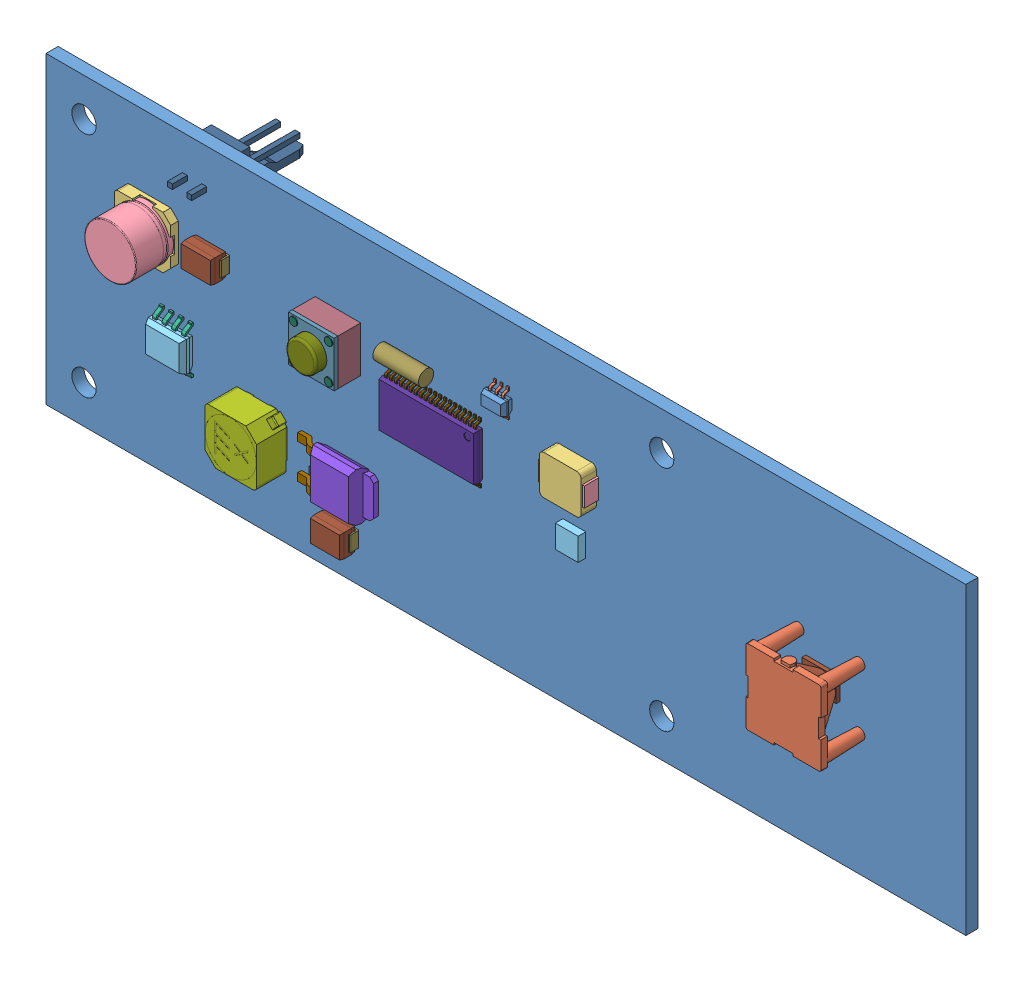
SolidWorks assembly CarteECLAI-YC, configuration Défaut. Lengths in mm.
Overall size (121 40 19.3).
110 component instances, 34 part files, 55 mates.
Components (placement in the parent):
- PCB-1: PCB [Défaut] at (-79.5148 -10.7674 -0.8) size (121 40 1.6)
- Lentille-1: Lentille [Défaut] at (23.4852 9.2326 6.65) x (-1 0 0) z (0 0 -1) size (9.9 9.95 6.4)
- C1-1: C1 [Défaut] at (-27.7034 54.9496 1.55) x (0 1 0) z (0 0 1) size (6.9 6.9 5.5)
  - C1_embase-1: C1_embase [Défaut] at (-42.0171 34.4114 -0.75) size (6.9 6.9 1.5)
  - C1_boitier-1: C1_boitier [Défaut] at (-38.5671 37.8614 -0.25) size (6.8 6.8 5)
- U1-1: U1 [Défaut] at (-30.9157 -18.9411 1.8647) size (5 6.2 1.94)
  - U1_boitier-1: U1_boitier [Défaut] at (-33.8554 22.1141 -0.875) size (5 4 1.75)
  - U1_pin-1: U1_pin [Défaut] at (-32.2404 26.1141 -0.875) x (-1 0 0) z (0 0 1) size (0.5 1.1 1.09)
  - U1_pin-2: U1_pin [Défaut] at (-33.5104 26.1141 -0.875) x (-1 0 0) z (0 0 1) size (0.5 1.1 1.09)
  - U1_pin-3: U1_pin [Défaut] at (-30.9704 26.1141 -0.875) x (-1 0 0) z (0 0 1) size (0.5 1.1 1.09)
  - U1_pin-4: U1_pin [Défaut] at (-29.7004 26.1141 -0.875) x (-1 0 0) z (0 0 1) size (0.5 1.1 1.09)
  - U1_pin-5: U1_pin [Défaut] at (-31.7404 22.1141 -0.875) size (0.5 1.1 1.09)
  - U1_pin-6: U1_pin [Défaut] at (-33.0104 22.1141 -0.875) size (0.5 1.1 1.09)
  - U1_pin-7: U1_pin [Défaut] at (-30.4704 22.1141 -0.875) size (0.5 1.1 1.09)
  - U1_pin-8: U1_pin [Défaut] at (-29.2004 22.1141 -0.875) size (0.5 1.1 1.09)
- L1-1: L1 [Default] at (-51.1156 0.6301 1) x (0 1 0) z (1 0 0) size (7.56 4.1 7.56)
- Q1-1: Q1 [Défaut] at (-47.9587 -45.8219 1.895) x (0 -1 0) z (0 0 1) size (6.35 10.04 2.19)
  - Q1_boitier-1: Q1_boitier [Défaut] at (-49.4045 4.9439 -1.095) size (6.35 7.24 2.19)
  - Q1_Pin-1: Q1_Pin [Défaut] at (-49.0095 2.1439 -0.505) x (0 0 -1) z (1 0 0) size (1.3 2.8 1)
  - Q1_Pin2-1: Q1_Pin2 [Défaut] at (-45.7295 5.2439 2.6813) x (0 1 0) z (-1 0 0) size (0.5 0.41 1)
  - Q1_Pin-2: Q1_Pin [Défaut] at (-44.4495 2.1439 -0.505) x (0 0 -1) z (1 0 0) size (1.3 2.8 1)
- D3-1: D3 [Défaut] at (-11.1435 -5.4674 2.6964) x (1 0 0) z (0 -1 0) size (4.4 2.3 3)
  - D3_boitier-1: D3_boitier [Défaut] at (-31.3713 -1.5964 1.5) size (4 2 3)
  - D3_pin-1: D3_pin [Défaut] at (-31.5713 -1.8964 -0.98) size (0.5 1.2 2)
  - D3_pin-2: D3_pin [Défaut] at (-27.1713 -1.8964 1.02) x (-1 0 0) z (0 0 -1) size (0.5 1.2 2)
- D3-2: D3 [Défaut] at (-28.1435 17.3326 2.6964) x (1 0 0) z (0 -1 0) size (4.4 2.3 3)
  - D3_boitier-1: D3_boitier [Défaut] at (-31.3713 -1.5964 1.5) size (4 2 3)
  - D3_pin-1: D3_pin [Défaut] at (-31.5713 -1.8964 -0.98) size (0.5 1.2 2)
  - D3_pin-2: D3_pin [Défaut] at (-27.1713 -1.8964 1.02) x (-1 0 0) z (0 0 -1) size (0.5 1.2 2)
- Switch-1: Switch [Défaut] at (-30.8503 16.2326 10.8345) x (1 0 0) z (0 -1 0) size (6 4.89 6)
  - Switch_Corps-1: Switch_Corps [Défaut] at (-13.2645 -10.0345 3) size (6 3 6)
  - Switch_Couvercle-1: Switch_Couvercle [Défaut] at (-13.2645 -7.0345 3) size (6 0.5 6)
  - Switch_Seri-1: Switch_Seri [Défaut] at (-12.5686 -6.4345 2.3041) x (-0.837169 0 -0.546944) z (-0.546944 0 0.837169) size (1 0.6 1)
  - Switch_Seri-2: Switch_Seri [Défaut] at (-7.9603 -6.4345 -2.3041) x (-0.837169 0 -0.546944) z (-0.546944 0 0.837169) size (1 0.6 1)
  - Switch_Seri-3: Switch_Seri [Défaut] at (-7.9603 -6.4345 2.3041) x (-0.837169 0 -0.546944) z (-0.546944 0 0.837169) size (1 0.6 1)
  - Switch_Seri-4: Switch_Seri [Défaut] at (-12.5686 -6.4345 -2.3041) x (-0.837169 0 -0.546944) z (-0.546944 0 0.837169) size (1 0.6 1)
  - Switch_Bp-1: Switch_Bp [Défaut] at (-10.2645 -8.1417 0) x (0.988647 0 0.150258) z (-0.150258 0 0.988647) size (4 3 4)
- U2-1: U2 [Défaut] at (-16.9345 12.3907 -2.7862) x (-1 0 0) z (0 1 0) size (12.6 1.27 7.96)
  - U2_Boitier-1: U2_Boitier [Défaut] at (4.9869 3.6612 3) size (12.6 1.2 6)
  - U2_Pin-1: U2_Pin [Défaut] at (11.1369 3.5862 3.9812) x (0 0 -1) z (1 0 0) size (0.98 0.78 0.3)
  - U2_Pin-2: U2_Pin [Défaut] at (10.4869 3.5862 3.9812) x (0 0 -1) z (1 0 0) size (0.98 0.78 0.3)
  - U2_Pin-3: U2_Pin [Défaut] at (9.8369 3.5862 3.9812) x (0 0 -1) z (1 0 0) size (0.98 0.78 0.3)
  - U2_Pin-4: U2_Pin [Défaut] at (9.1869 3.5862 3.9812) x (0 0 -1) z (1 0 0) size (0.98 0.78 0.3)
  - U2_Pin-5: U2_Pin [Défaut] at (8.5369 3.5862 3.9812) x (0 0 -1) z (1 0 0) size (0.98 0.78 0.3)
  - U2_Pin-6: U2_Pin [Défaut] at (7.8869 3.5862 3.9812) x (0 0 -1) z (1 0 0) size (0.98 0.78 0.3)
  - U2_Pin-7: U2_Pin [Défaut] at (7.2369 3.5862 3.9812) x (0 0 -1) z (1 0 0) size (0.98 0.78 0.3)
  - U2_Pin-8: U2_Pin [Défaut] at (6.5869 3.5862 3.9812) x (0 0 -1) z (1 0 0) size (0.98 0.78 0.3)
  - U2_Pin-9: U2_Pin [Défaut] at (5.9369 3.5862 3.9812) x (0 0 -1) z (1 0 0) size (0.98 0.78 0.3)
  - U2_Pin-12: U2_Pin [Défaut] at (11.7869 3.5862 3.9812) x (0 0 -1) z (1 0 0) size (0.98 0.78 0.3)
  - U2_Pin-13: U2_Pin [Défaut] at (12.4369 3.5862 3.9812) x (0 0 -1) z (1 0 0) size (0.98 0.78 0.3)
  - U2_Pin-14: U2_Pin [Défaut] at (13.0869 3.5862 3.9812) x (0 0 -1) z (1 0 0) size (0.98 0.78 0.3)
  - U2_Pin-15: U2_Pin [Défaut] at (13.7369 3.5862 3.9812) x (0 0 -1) z (1 0 0) size (0.98 0.78 0.3)
  - U2_Pin-16: U2_Pin [Défaut] at (14.3869 3.5862 3.9812) x (0 0 -1) z (1 0 0) size (0.98 0.78 0.3)
  - U2_Pin-17: U2_Pin [Défaut] at (15.0369 3.5862 3.9812) x (0 0 -1) z (1 0 0) size (0.98 0.78 0.3)
  - U2_Pin-18: U2_Pin [Défaut] at (15.6869 3.5862 3.9812) x (0 0 -1) z (1 0 0) size (0.98 0.78 0.3)
  - U2_Pin-19: U2_Pin [Défaut] at (16.3369 3.5862 3.9812) x (0 0 -1) z (1 0 0) size (0.98 0.78 0.3)
  - U2_Pin-21: U2_Pin [Défaut] at (5.2869 3.5862 3.9812) x (0 0 -1) z (1 0 0) size (0.98 0.78 0.3)
  - U2_Pin-22: U2_Pin [Défaut] at (16.9869 3.5862 3.9812) x (0 0 -1) z (1 0 0) size (0.98 0.78 0.3)
  - U2_Pin-23: U2_Pin [Défaut] at (11.4369 3.5862 -3.9812) x (0 0 1) z (-1 0 0) size (0.98 0.78 0.3)
  - U2_Pin-24: U2_Pin [Défaut] at (12.0869 3.5862 -3.9812) x (0 0 1) z (-1 0 0) size (0.98 0.78 0.3)
  - U2_Pin-26: U2_Pin [Défaut] at (12.7369 3.5862 -3.9812) x (0 0 1) z (-1 0 0) size (0.98 0.78 0.3)
  - U2_Pin-27: U2_Pin [Défaut] at (13.3869 3.5862 -3.9812) x (0 0 1) z (-1 0 0) size (0.98 0.78 0.3)
  - U2_Pin-28: U2_Pin [Défaut] at (14.0369 3.5862 -3.9812) x (0 0 1) z (-1 0 0) size (0.98 0.78 0.3)
  - U2_Pin-29: U2_Pin [Défaut] at (14.6869 3.5862 -3.9812) x (0 0 1) z (-1 0 0) size (0.98 0.78 0.3)
  - U2_Pin-30: U2_Pin [Défaut] at (15.3369 3.5862 -3.9812) x (0 0 1) z (-1 0 0) size (0.98 0.78 0.3)
  - U2_Pin-31: U2_Pin [Défaut] at (15.9869 3.5862 -3.9812) x (0 0 1) z (-1 0 0) size (0.98 0.78 0.3)
  - U2_Pin-32: U2_Pin [Défaut] at (16.6369 3.5862 -3.9812) x (0 0 1) z (-1 0 0) size (0.98 0.78 0.3)
  - U2_Pin-33: U2_Pin [Défaut] at (17.2869 3.5862 -3.9812) x (0 0 1) z (-1 0 0) size (0.98 0.78 0.3)
  - U2_Pin-34: U2_Pin [Défaut] at (10.7869 3.5862 -3.9812) x (0 0 1) z (-1 0 0) size (0.98 0.78 0.3)
  - U2_Pin-35: U2_Pin [Défaut] at (10.1369 3.5862 -3.9812) x (0 0 1) z (-1 0 0) size (0.98 0.78 0.3)
  - U2_Pin-36: U2_Pin [Défaut] at (9.4869 3.5862 -3.9812) x (0 0 1) z (-1 0 0) size (0.98 0.78 0.3)
  - U2_Pin-37: U2_Pin [Défaut] at (8.8369 3.5862 -3.9812) x (0 0 1) z (-1 0 0) size (0.98 0.78 0.3)
  - U2_Pin-38: U2_Pin [Défaut] at (8.1869 3.5862 -3.9812) x (0 0 1) z (-1 0 0) size (0.98 0.78 0.3)
  - U2_Pin-39: U2_Pin [Défaut] at (7.5369 3.5862 -3.9812) x (0 0 1) z (-1 0 0) size (0.98 0.78 0.3)
  - U2_Pin-40: U2_Pin [Défaut] at (6.8869 3.5862 -3.9812) x (0 0 1) z (-1 0 0) size (0.98 0.78 0.3)
  - U2_Pin-41: U2_Pin [Défaut] at (6.2369 3.5862 -3.9812) x (0 0 1) z (-1 0 0) size (0.98 0.78 0.3)
  - U2_Pin-42: U2_Pin [Défaut] at (5.5869 3.5862 -3.9812) x (0 0 1) z (-1 0 0) size (0.98 0.78 0.3)
- U3-1: U3 [Défaut] at (-9.125 -11.1977 1.55) size (3 3.71 1.47)
  - U3_boitier-1: U3_boitier [Défaut] at (-11.8964 30.2254 -0.725) size (3 1.75 1.45)
  - U3_Pin-1: U3_Pin [Défaut] at (-10.5464 30.2254 0.025) x (0 -1 0) z (1 0 0) size (0.98 0.78 0.3)
  - U3_Pin-2: U3_Pin [Défaut] at (-11.3964 30.2254 0.025) x (0 -1 0) z (1 0 0) size (0.98 0.78 0.3)
  - U3_Pin-5: U3_Pin [Défaut] at (-9.6964 30.2254 0.025) x (0 -1 0) z (1 0 0) size (0.98 0.78 0.3)
  - U3_Pin-6: U3_Pin [Défaut] at (-10.2464 32.9566 -0.75) x (0 -1 0) z (-1 0 0) size (0.98 0.78 0.3)
  - U3_Pin-7: U3_Pin [Défaut] at (-11.0964 32.9566 -0.75) x (0 -1 0) z (-1 0 0) size (0.98 0.78 0.3)
  - U3_Pin-8: U3_Pin [Défaut] at (-9.3964 32.9566 -0.75) x (0 -1 0) z (-1 0 0) size (0.98 0.78 0.3)
- L2-1: L2 [Défaut] at (28.7972 -10.0998 1.9) size (6.05 5.18 2.1)
  - L2_boitier-1: L2_boitier [Défaut] at (-41.3121 23.5524 -1) size (5.49 5.18 2)
  - L2_pin-1: L2_pin [Défaut] at (-35.8421 24.8724 -0.8) x (-1 0 0) z (0 0 -1) size (1.3 2.54 1.95)
  - L2_pin-2: L2_pin [Défaut] at (-41.2921 27.4124 -0.8) x (1 0 0) z (0 0 -1) size (1.3 2.54 1.95)
- U4-1: U4 [Défaut] at (-11.5148 7.2326 0.8) size (3 3 1)
- R_J6-1: R_J6 [Défaut] at (-48.0148 -7.2951 -15.102) x (0 -0.870538 0.492102) z (-1 0 0) size (4.71 4.44 24.2)
  - R_corps-1: R_corps [Défaut] at (-14.9486 23.7304 -11.5) size (2 2 23)
  - R_fil-1: R_fil [Défaut] at (-14.9486 23.7304 -11.5) x (0.735085 -0.677975 0) z (0.677975 0.735085 0) size (5.06 11.19 0.2)
  - R_fil-2: R_fil [Défaut] at (-14.9486 23.7304 11.5) x (0.735085 -0.677975 0) z (-0.677975 -0.735085 0) size (5.06 11.19 0.2)
- R_J5_J17-1: R_J5_J17 [Défaut] at (-1.4671 6.7792 26.1941) x (-0.812051 0 0.583586) z (0 -1 0) size (4.54 4.6 24.2)
  - R_corps-1: R_corps [Défaut] at (-14.9486 23.7304 -11.5) size (2 2 23)
  - R_fil_court-2: R_fil_court [Défaut] at (-14.9486 23.7304 11.5) x (0.700956 0.713204 0) z (0.713204 -0.700956 0) size (4.95 5.14 0.2)
  - R_fil_long-4: R_fil_long [Défaut] at (-14.9486 23.7304 -11.5) x (0.700956 0.713204 0) z (-0.713204 0.700956 0) size (5.05 17.25 0.2)
- R_J5_J17-2: R_J5_J17 [Défaut] at (-70.8253 9.7326 26.2305) x (0.827762 0 0.56108) z (0 1 0) size (4.54 4.6 24.2)
  - R_corps-1: R_corps [Défaut] at (-14.9486 23.7304 -11.5) size (2 2 23)
  - R_fil_court-2: R_fil_court [Défaut] at (-14.9486 23.7304 11.5) x (0.700956 0.713204 0) z (0.713204 -0.700956 0) size (4.95 5.14 0.2)
  - R_fil_long-4: R_fil_long [Défaut] at (-14.9486 23.7304 -11.5) x (0.700956 0.713204 0) z (-0.713204 0.700956 0) size (5.05 17.25 0.2)
- 4357-1: 4357 [Default] at (-59.9748 24.3126 -2.38) x (1 0 0) z (0 1 0) size (5.08 15.26 5.8)
  - 4357_01-1: 4357_01 [Default] at origin size (1.19 0 0.6)
  - 4357_02-1: 4357_02 [Default] at origin size (5.08 15.26 5.8)
  - 4357_03-1: 4357_03 [Default] at origin size (1.19 0 0.6)
  - 4357_04-1: 4357_04 [Default] at origin size (1.19 0 0.6)
  - 4357_05-1: 4357_05 [Default] at origin size (1.19 0 0.6)
- Led-1: Led [Défaut] at (23.4852 9.2326 1.3895) x (0 -1 0) z (0 0 1) size (3.32 4.77 2.78)
- Quartz-1: Quartz [Défaut] at (-34.5148 18.2781 1.8) x (0 0.581227 -0.813742) z (1 0 0) size (2 2 6)
Mates (geometry in assembly coordinates):
- Coaxiale4: concentric anti-aligned: circle of PCB-1; circle of Lentille-1
- Coaxiale5: concentric anti-aligned: circle of PCB-1; circle of Lentille-1
- Coïncidente3: coincident anti-aligned: plane of PCB-1 through (-79.5148 29.2326 0.8) normal (0 0 1); plane of Lentille-1 through (19.4852 13.2326 0.8) normal (0 0 -1)
- Parallèle1: parallel aligned: line of PCB-1 through (-79.5148 29.2326 0.8) axis (0 -1 0); line of C1-1/C1_embase-1 through (-69.0148 19.3326 0.8) axis (0 -1 0)
- Coïncidente5: coincident anti-aligned: plane of PCB-1 through (-79.5148 29.2326 0.8) normal (0 0 1); plane of C1-1/C1_embase-1 through (-69.0148 12.9326 0.8) normal (0 0 -1)
- Distance2: distance = 10.5 mm: line of C1-1/C1_embase-1 through (-69.0148 19.3326 0.8) axis (0 -1 0); line of PCB-1 through (-79.5148 29.2326 0.8) axis (0 -1 0)
- Distance3: distance = 9.4 mm: line of C1-1/C1_embase-1 through (-63.1148 19.8326 0.8) axis (-1 0 0); line of PCB-1 through (41.4852 29.2326 0.8) axis (-1 0 0)
- Coïncidente8: coincident anti-aligned: plane of PCB-1 through (-79.5148 29.2326 0.8) normal (0 0 1); plane of U1-1/U1_pin-3 through (-61.3861 2.3483 0.8) normal (0 0 -1)
- Distance4: distance = 14.8 mm: line of U1-1/U1_boitier-1 through (-64.7711 3.173 2.0897) axis (0 1 0); line of PCB-1 through (-79.5148 29.2326 0.8) axis (0 -1 0)
- Distance5: distance = 14 mm: line of U1-1/U1_boitier-1 through (-59.7711 3.173 2.0897) axis (-1 0 0); line of PCB-1 through (-79.5148 -10.7674 0.8) axis (1 0 0)
- Coïncidente11: coincident anti-aligned: plane of PCB-1 through (-79.5148 29.2326 0.8) normal (0 0 1); plane of L1-1 through (-51.1156 0.6301 0.8) normal (0 0 -1)
- Parallèle2: parallel aligned: plane of PCB-1 through (-79.5148 -10.7674 0.8) normal (0 -1 0); plane of L1-1 through (-54.5156 -2.7699 4.9) normal (0 -1 0)
- Distance6: distance = 8 mm: line of L1-1 through (-48.2156 -2.7699 1) axis (-1 0 0); line of PCB-1 through (-79.5148 -10.7674 0.8) axis (1 0 0)
- Distance7: distance = 25 mm: line of L1-1 through (-54.5156 -1.3499 1) axis (0 1 0); line of PCB-1 through (-79.5148 29.2326 0.8) axis (0 -1 0)
- Coïncidente15: coincident anti-aligned: plane of PCB-1 through (-79.5148 29.2326 0.8) normal (0 0 1); plane of Q1-1/Q1_boitier-1 through (-37.0448 3.5826 0.8) normal (0 0 -1)
- Parallèle3: parallel aligned: plane of PCB-1 through (-79.5148 -10.7674 0.8) normal (0 -1 0); plane of Q1-1/Q1_boitier-1 through (-43.0148 -2.7674 2.99) normal (0 -1 0)
- Distance8: distance = 8 mm aligned: plane of Q1-1/Q1_boitier-1 through (-43.0148 -2.7674 2.99) normal (0 -1 0); plane of PCB-1 through (-79.5148 -10.7674 0.8) normal (0 -1 0)
- Distance9: distance = 36.5 mm aligned: plane of Q1-1/Q1_boitier-1 through (-43.0148 3.5826 2.99) normal (-1 0 0); plane of PCB-1 through (-79.5148 -10.7674 0.8) normal (-1 0 0)
- Coïncidente19: coincident anti-aligned: plane of PCB-1 through (-79.5148 29.2326 0.8) normal (0 0 1); plane of D3-1/D3_pin-2 through (-38.4148 -4.4874 0.8) normal (0 0 -1)
- Distance10: distance = 3.8 mm aligned: plane of D3-1/D3_boitier-1 through (-42.5148 -6.9674 3.1) normal (0 -1 0); plane of PCB-1 through (-79.5148 -10.7674 0.8) normal (0 -1 0)
- Distance11: distance = 37 mm aligned: plane of D3-1/D3_boitier-1 through (-42.5148 -6.9674 3.1) normal (-1 0 0); plane of PCB-1 through (-79.5148 -10.7674 0.8) normal (-1 0 0)
- Coïncidente22: coincident anti-aligned: plane of PCB-1 through (-79.5148 29.2326 0.8) normal (0 0 1); plane of D3-2/D3_pin-1 through (-59.6148 16.3126 0.8) normal (0 0 -1)
- Distance12: distance = 10.4 mm aligned: plane of D3-2/D3_boitier-1 through (-59.5148 18.8326 3.1) normal (0 1 0); plane of PCB-1 through (-79.5148 29.2326 0.8) normal (0 1 0)
- Distance13: distance = 20 mm aligned: plane of D3-2/D3_boitier-1 through (-59.5148 15.8326 3.1) normal (-1 0 0); plane of PCB-1 through (-79.5148 -10.7674 0.8) normal (-1 0 0)
- Coïncidente25: coincident anti-aligned: plane of PCB-1 through (-79.5148 29.2326 0.8) normal (0 0 1); plane of Switch-1/Switch_Corps-1 through (-44.1148 13.2326 0.8) normal (0 0 -1)
- Distance14: distance = 10 mm aligned: plane of Switch-1/Switch_Corps-1 through (-44.1148 19.2326 3.8) normal (0 1 0); plane of PCB-1 through (-79.5148 29.2326 0.8) normal (0 1 0)
- Distance15: distance = 35.4 mm aligned: plane of Switch-1/Switch_Corps-1 through (-44.1148 13.2326 3.8) normal (-1 0 0); plane of PCB-1 through (-79.5148 -10.7674 0.8) normal (-1 0 0)
- Coïncidente28: coincident anti-aligned: plane of PCB-1 through (-79.5148 29.2326 0.8) normal (0 0 1); plane of U2-1/U2_Pin-5 through (-25.7715 16.3719 0.8) normal (0 0 -1)
- Parallèle4: parallel aligned: line of PCB-1 through (41.4852 29.2326 0.8) axis (-1 0 0); line of U2-1/U2_Boitier-1 through (-22.0215 15.2907 2.075) axis (-1 0 0)
- Distance16: distance = 45 mm: line of U2-1/U2_Boitier-1 through (-34.5215 9.3907 1.575) axis (0 1 0); line of PCB-1 through (-79.5148 29.2326 0.8) axis (0 -1 0)
- Distance17: distance = 14 mm: line of U2-1/U2_Boitier-1 through (-22.0215 15.2907 2.075) axis (-1 0 0); line of PCB-1 through (41.4852 29.2326 0.8) axis (-1 0 0)
- Coïncidente32: coincident anti-aligned: plane of PCB-1 through (-79.5148 29.2326 0.8) normal (0 0 1); plane of U3-1/U3_Pin-6 through (-19.6713 21.7589 0.8) normal (0 0 -1)
- Distance18: distance = 8.5 mm: line of U3-1/U3_boitier-1 through (-21.0213 20.7777 1.675) axis (1 0 0); line of PCB-1 through (41.4852 29.2326 0.8) axis (-1 0 0)
- Distance19: distance = 58.5 mm: line of U3-1/U3_boitier-1 through (-21.0213 19.0277 1.675) axis (0 1 0); line of PCB-1 through (-79.5148 29.2326 0.8) axis (0 -1 0)
- Coïncidente35: coincident anti-aligned: plane of PCB-1 through (-79.5148 29.2326 0.8) normal (0 0 1); plane of L2-1/L2_pin-1 through (-6.8448 17.3126 0.8) normal (0 0 -1)
- Distance20: distance = 67 mm aligned: plane of L2-1/L2_boitier-1 through (-12.5148 13.4526 2.9) normal (-1 0 0); plane of PCB-1 through (-79.5148 -10.7674 0.8) normal (-1 0 0)
- Distance21: distance = 10.6 mm aligned: plane of L2-1/L2_boitier-1 through (-12.5148 18.6326 2.9) normal (0 1 0); plane of PCB-1 through (-79.5148 29.2326 0.8) normal (0 1 0)
- Coïncidente38: coincident anti-aligned: plane of PCB-1 through (-79.5148 29.2326 0.8) normal (0 0 1); plane of U4-1 through (-11.5148 10.2326 0.8) normal (0 0 -1)
- Distance22: distance = 19 mm aligned: plane of U4-1 through (-11.5148 10.2326 1.8) normal (0 1 0); plane of PCB-1 through (-79.5148 29.2326 0.8) normal (0 1 0)
- Distance23: distance = 68 mm aligned: plane of U4-1 through (-11.5148 7.2326 1.8) normal (-1 0 0); plane of PCB-1 through (-79.5148 -10.7674 0.8) normal (-1 0 0)
- Parallèle5: parallel anti-aligned: line of PCB-1 through (41.4852 29.2326 -0.8) axis (-1 0 0); cylinder of R_J6-1/R_corps-1 through (-59.5148 17.396 -1.8) axis (1 0 0) radius 1
- Distance25: distance = 20 mm aligned: plane of R_J6-1/R_corps-1 through (-59.5148 17.396 -1.8) normal (-1 0 0); plane of PCB-1 through (-79.5148 -10.7674 0.8) normal (-1 0 0)
- Verrouiller4: lock: unknown of PCB-1; unknown of R_J5_J17-1/R_corps-1
- Parallèle6: parallel anti-aligned: line of PCB-1 through (-79.5148 29.2326 -0.8) axis (0 -1 0); cylinder of R_J5_J17-1/R_corps-1 through (-3.1769 -4.7208 -1.8) axis (0 1 0) radius 1
- Parallèle7: parallel aligned: line of PCB-1 through (-79.5148 29.2326 -0.8) axis (0 -1 0); cylinder of R_J5_J17-2/R_corps-1 through (-69.8845 21.2326 -1.8) axis (0 -1 0) radius 1
- Coïncidente49: coincident anti-aligned: plane of PCB-1 through (-79.5148 29.2326 -0.8) normal (0 0 -1); plane of 4357-1/4357_02-1 through (-62.5148 27.2326 -0.8) normal (0 0 1)
- Parallèle8: parallel anti-aligned: plane of PCB-1 through (-79.5148 29.2326 0.8) normal (0 1 0); plane of 4357-1/4357_02-1 through (-62.5148 21.4326 -0.8) normal (0 -1 0)
- Distance28: distance = 17 mm aligned: plane of 4357-1/4357_02-1 through (-62.5148 24.3126 -2.38) normal (-1 0 0); plane of PCB-1 through (-79.5148 -10.7674 0.8) normal (-1 0 0)
- Distance29: distance = 2 mm aligned: plane of 4357-1/4357_02-1 through (-62.5148 27.2326 -3.96) normal (0 1 0); plane of PCB-1 through (-79.5148 29.2326 0.8) normal (0 1 0)
- Coïncidente53: coincident anti-aligned: plane of PCB-1 through (-79.5148 29.2326 0.8) normal (0 0 1); plane of Led-1 through (24.8852 10.6326 0.8) normal (0 0 -1)
- Parallèle9: parallel anti-aligned: line of Lentille-1 through (28.4369 10.4559 5.95) axis (0 1 0); line of Led-1 through (25.0102 10.7576 1.3895) axis (0 -1 0)
- Coaxiale9: concentric anti-aligned: cone of Lentille-1 through (23.4852 9.2326 1.8) axis (0 0 1); cylinder of Led-1 through (23.4852 9.2326 1) axis (0 0 -1) radius 0.5
- Tangent9: tangent anti-aligned: plane of PCB-1 through (-79.5148 29.2326 0.8) normal (0 0 1); cylinder of Quartz-1 through (-28.5148 18.2781 1.8) axis (-1 0 0) radius 1
- Distance30: distance = 76 mm anti-aligned: plane of PCB-1 through (41.4852 -10.7674 0.8) normal (1 0 0); plane of Quartz-1 through (-34.5148 18.2781 1.8) normal (-1 0 0)
- Distance31: distance = 10 mm: cylinder of Quartz-1 through (-28.5148 18.2781 1.8) axis (-1 0 0) radius 1; line of PCB-1 through (41.4852 29.2326 0.8) axis (-1 0 0)
